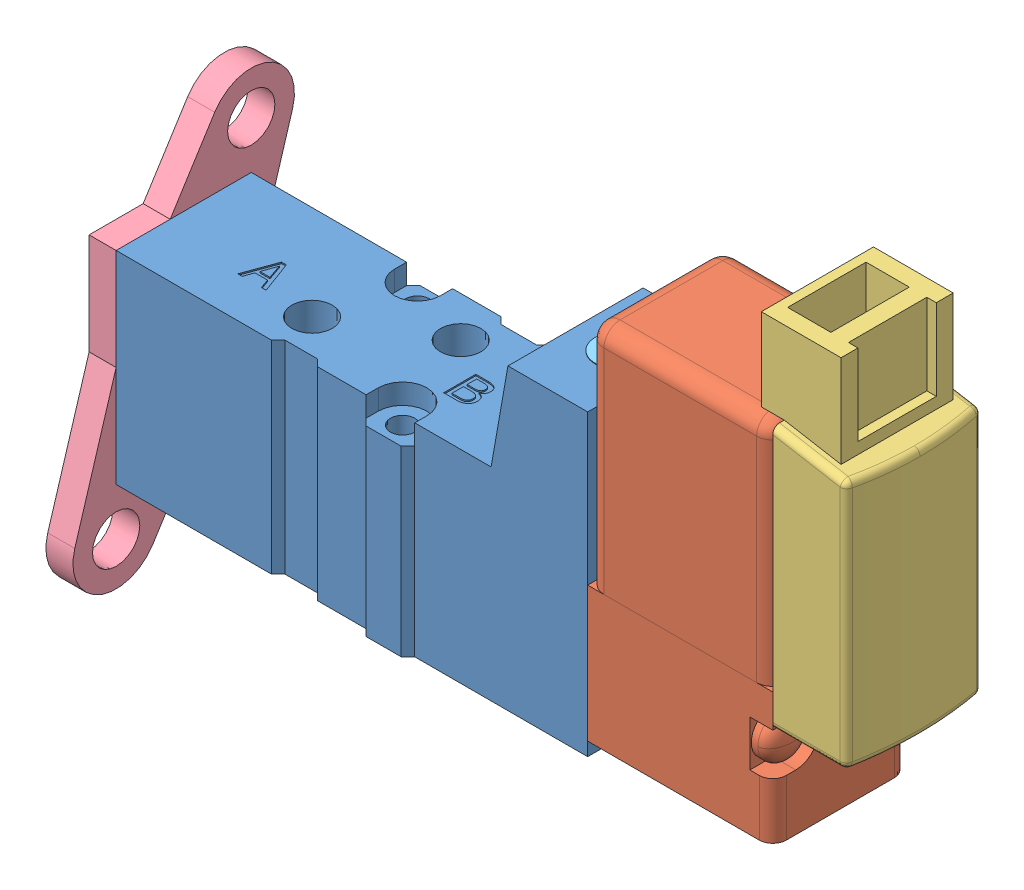
SolidWorks assembly SYJ3120-SMO-M3-F, configuration Default. Lengths in mm.
Overall size (56.5 40.8 16.4).
6 component instances, 5 part files, 0 mates.
Components (placement in the parent):
- SYJ3120-SMO-M3-F.step_SYJ3000VALVEBODY_SYJ3120-1: SYJ3120-SMO-M3-F.step_SYJ3000VALVEBODY_SYJ3120 [Default] at origin size (34.9 22.1 11)
- SYJ3120-SMO-M3-F.step_V100_V111-SMO-1: SYJ3120-SMO-M3-F.step_V100_V111-SMO [Default] at (19.9 1 0) x (0 -1 0) z (0 0 1) size (33.1 22.4 10)
  - SYJ3120-SMO-M3-F.step_V100_1-1: SYJ3120-SMO-M3-F.step_V100_1 [Default] at origin size (27 16.5 10)
  - SYJ3120-SMO-M3-F.step_V100 Cover_M-1: SYJ3120-SMO-M3-F.step_V100 Cover_M [Default] at (-7.55 13.7 0) size (25.55 7.6 10)
- SYJ3120-SMO-M3-F.step_SYJ3000BRACKET-1: SYJ3120-SMO-M3-F.step_SYJ3000BRACKET [Default] at (-15 7.5 0) x (0 1 0) z (0 0 1) size (28.4 2 16.4)
- SYJ3120-SMO-M3-F.step_MAN-OP_Blue_P-1: SYJ3120-SMO-M3-F.step_MAN-OP_Blue_P [Default] at (17.1 21.65 0) size (3.3 0.5 3.3)
